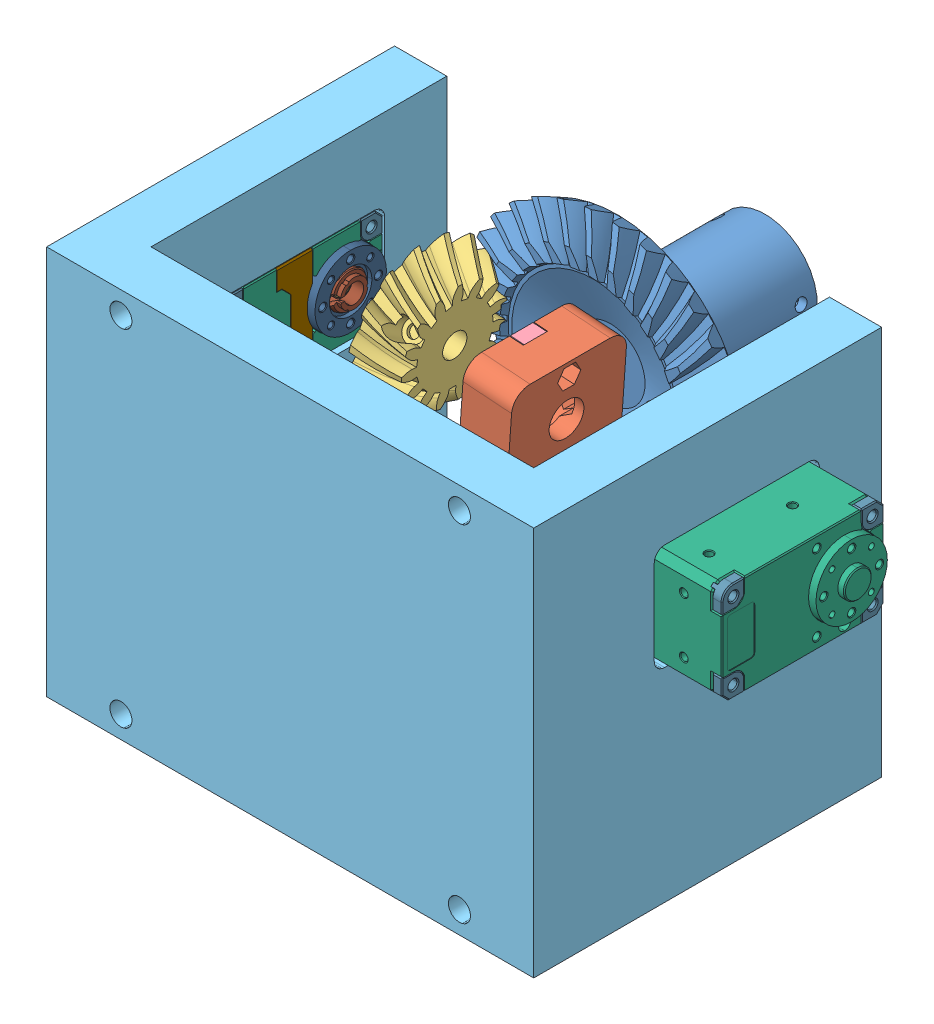
SolidWorks assembly ARMUS-100-000, configuration Défaut. Lengths in mm.
Overall size (185.8 148.44 136.49).
56 component instances, 14 part files, 17 mates.
Components (placement in the parent):
- ARMUS-100-001-1: ARMUS-100-001 [Default] at (-113.5896 14.9753 27.4558) x (-0.928119 0.372284 0) z (0 0 1) size (98.61 98.7 51.05)
- ARMUS-100-002-1: ARMUS-100-002 [Default] at (-113.5896 14.9753 49.0303) x (0.070839 0.997488 0) z (0.997488 -0.070839 0) size (29.97 33 14)
- ARMUS-100-003-1: ARMUS-100-003 [Default] at (-151.1032 17.6395 49.0303) x (0.0431 0.606897 -0.793611) z (0.997488 -0.070839 0) size (43.82 43.82 12.4)
- ARMUS-100-003-2: ARMUS-100-003 [Default] at (-74.4243 12.1939 49.0303) x (-0.070618 -0.99438 -0.078881) z (-0.997488 0.070839 0) size (43.82 43.82 12.4)
- ARMUS-100-004-1: ARMUS-100-004 [Default] at (-116.5821 15.1878 49.0303) x (0.070839 0.997488 0) z (-0.997488 0.070839 0) size (30 15.8 4)
- ARMUS-100-006-1: ARMUS-100-006 [Défaut] at (-74.0766 50.6459 21.4485) size (177.55 139.4 100)
- ARMUS-100-005.stp-1: ARMUS-100-005.stp [Défaut] at (-185.6063 17.2977 51.066) x (0 1 0) z (-1 0 0) size (28.5 46.5 40.9)
  - DC11_A01_DUMMY.stp-1: DC11_A01_DUMMY.stp [Défaut] at origin size (28.5 46.5 37.9)
  - DX124_SCREW-COVER.stp-1: DX124_SCREW-COVER.stp [Défaut] at (11.75 0 13.7) x (-1 0 0) z (0 1 0) size (3.5 30.65 3.5)
  - B3B-EH.stp-1: B3B-EH.stp [Défaut] at (10.15 -14.1 -3.8) x (0 -1 0) z (1 0 0) size (10 9.2 3.8)
  - B3B-EH.stp-2: B3B-EH.stp [Défaut] at (-10.15 -14.1 -3.8) x (0 1 0) z (-1 0 0) size (10 9.2 3.8)
  - DC11_A01_CASE_CVR_DUMMY.stp-1: DC11_A01_CASE_CVR_DUMMY.stp [Défaut] at origin size (28.3 17.62 8.31)
  - DC11_A01_IDLER_DUMMY.stp-1: DC11_A01_IDLER_DUMMY.stp [Défaut] at (0 0 -19) x (1 0 0) z (0 1 0) size (20.5 3.5 20.5)
  - DC11_A01_IDLER_CAP_DUMMY.stp-1: DC11_A01_IDLER_CAP_DUMMY.stp [Défaut] at (0 0 -18.8) x (1 0 0) z (0 -1 0) size (10.1 5.2 10.37)
  - DC11_A01_IDLER_SCREW.stp-1: DC11_A01_IDLER_SCREW.stp [Défaut] at (0 0 -15.1) x (-1 0 0) z (0 -1 0) size (5 5.01 5)
  - FHS_M2_5X10.stp-1: FHS_M2_5X10.stp [Défaut] at (11 8 12.95) x (-1 0 0) z (0 1 0) size (5 10.01 5)
  - FHS_M2_5X10.stp-2: FHS_M2_5X10.stp [Défaut] at (-11 8 12.95) x (-1 0 0) z (0 1 0) size (5 10.01 5)
  - FHS_M2_5X10.stp-3: FHS_M2_5X10.stp [Défaut] at (-11 -32 12.95) x (-1 0 0) z (0 1 0) size (5 10.01 5)
  - FHS_M2_5X10.stp-4: FHS_M2_5X10.stp [Défaut] at (11 -32 12.95) x (-1 0 0) z (0 1 0) size (5 10.01 5)
  - FHS_M2_5X10.stp-5: FHS_M2_5X10.stp [Défaut] at (-11 8 -12.95) x (1 0 0) z (0 1 0) size (5 10.01 5)
  - FHS_M2_5X10.stp-6: FHS_M2_5X10.stp [Défaut] at (11 8 -12.95) x (1 0 0) z (0 1 0) size (5 10.01 5)
  - FHS_M2_5X10.stp-7: FHS_M2_5X10.stp [Défaut] at (-11 -32 -12.95) x (1 0 0) z (0 1 0) size (5 10.01 5)
  - FHS_M2_5X10.stp-8: FHS_M2_5X10.stp [Défaut] at (11 -32 -12.95) x (1 0 0) z (0 1 0) size (5 10.01 5)
  - DC11_A01_SPACER_DUMMY.stp-1: DC11_A01_SPACER_DUMMY.stp [Défaut] at (11 8 14.2) x (-1 0 0) z (0 0 1) size (6.5 6.5 3.9)
  - DC11_A01_SPACER_DUMMY.stp-2: DC11_A01_SPACER_DUMMY.stp [Défaut] at (-11 8 14.2) x (0 -1 0) z (0 0 1) size (6.5 6.5 3.9)
  - DC11_A01_SPACER_DUMMY.stp-3: DC11_A01_SPACER_DUMMY.stp [Défaut] at (-11 -32 14.2) x (-1 0 0) z (0 0 1) size (6.5 6.5 3.9)
  - DC11_A01_SPACER_DUMMY.stp-4: DC11_A01_SPACER_DUMMY.stp [Défaut] at (11 -32 14.2) x (0 1 0) z (0 0 1) size (6.5 6.5 3.9)
  - DC11_A01_SPACER_DUMMY.stp-5: DC11_A01_SPACER_DUMMY.stp [Défaut] at (11 8 -14.2) x (0 -1 0) z (0 0 -1) size (6.5 6.5 3.9)
  - DC11_A01_SPACER_DUMMY.stp-6: DC11_A01_SPACER_DUMMY.stp [Défaut] at (-11 8 -14.2) x (1 0 0) z (0 0 -1) size (6.5 6.5 3.9)
  - DC11_A01_SPACER_DUMMY.stp-7: DC11_A01_SPACER_DUMMY.stp [Défaut] at (11 -32 -14.2) x (-1 0 0) z (0 0 -1) size (6.5 6.5 3.9)
  - DC11_A01_SPACER_DUMMY.stp-8: DC11_A01_SPACER_DUMMY.stp [Défaut] at (-11 -32 -14.2) x (0 1 0) z (0 0 -1) size (6.5 6.5 3.9)
- ARMUS-100-005.stp-2: ARMUS-100-005.stp [Défaut] at (-41.6063 17.2977 51.066) x (0 -1 0) z (1 0 0) size (28.5 46.5 40.9)
  - DC11_A01_DUMMY.stp-1: DC11_A01_DUMMY.stp [Défaut] at origin size (28.5 46.5 37.9)
  - DX124_SCREW-COVER.stp-1: DX124_SCREW-COVER.stp [Défaut] at (11.75 0 13.7) x (-1 0 0) z (0 1 0) size (3.5 30.65 3.5)
  - B3B-EH.stp-1: B3B-EH.stp [Défaut] at (10.15 -14.1 -3.8) x (0 -1 0) z (1 0 0) size (10 9.2 3.8)
  - B3B-EH.stp-2: B3B-EH.stp [Défaut] at (-10.15 -14.1 -3.8) x (0 1 0) z (-1 0 0) size (10 9.2 3.8)
  - DC11_A01_CASE_CVR_DUMMY.stp-1: DC11_A01_CASE_CVR_DUMMY.stp [Défaut] at origin size (28.3 17.62 8.31)
  - DC11_A01_IDLER_DUMMY.stp-1: DC11_A01_IDLER_DUMMY.stp [Défaut] at (0 0 -19) x (1 0 0) z (0 1 0) size (20.5 3.5 20.5)
  - DC11_A01_IDLER_CAP_DUMMY.stp-1: DC11_A01_IDLER_CAP_DUMMY.stp [Défaut] at (0 0 -18.8) x (1 0 0) z (0 -1 0) size (10.1 5.2 10.37)
  - DC11_A01_IDLER_SCREW.stp-1: DC11_A01_IDLER_SCREW.stp [Défaut] at (0 0 -15.1) x (-1 0 0) z (0 -1 0) size (5 5.01 5)
  - FHS_M2_5X10.stp-1: FHS_M2_5X10.stp [Défaut] at (11 8 12.95) x (-1 0 0) z (0 1 0) size (5 10.01 5)
  - FHS_M2_5X10.stp-2: FHS_M2_5X10.stp [Défaut] at (-11 8 12.95) x (-1 0 0) z (0 1 0) size (5 10.01 5)
  - FHS_M2_5X10.stp-3: FHS_M2_5X10.stp [Défaut] at (-11 -32 12.95) x (-1 0 0) z (0 1 0) size (5 10.01 5)
  - FHS_M2_5X10.stp-4: FHS_M2_5X10.stp [Défaut] at (11 -32 12.95) x (-1 0 0) z (0 1 0) size (5 10.01 5)
  - FHS_M2_5X10.stp-5: FHS_M2_5X10.stp [Défaut] at (-11 8 -12.95) x (1 0 0) z (0 1 0) size (5 10.01 5)
  - FHS_M2_5X10.stp-6: FHS_M2_5X10.stp [Défaut] at (11 8 -12.95) x (1 0 0) z (0 1 0) size (5 10.01 5)
  - FHS_M2_5X10.stp-7: FHS_M2_5X10.stp [Défaut] at (-11 -32 -12.95) x (1 0 0) z (0 1 0) size (5 10.01 5)
  - FHS_M2_5X10.stp-8: FHS_M2_5X10.stp [Défaut] at (11 -32 -12.95) x (1 0 0) z (0 1 0) size (5 10.01 5)
  - DC11_A01_SPACER_DUMMY.stp-1: DC11_A01_SPACER_DUMMY.stp [Défaut] at (11 8 14.2) x (-1 0 0) z (0 0 1) size (6.5 6.5 3.9)
  - DC11_A01_SPACER_DUMMY.stp-2: DC11_A01_SPACER_DUMMY.stp [Défaut] at (-11 8 14.2) x (0 -1 0) z (0 0 1) size (6.5 6.5 3.9)
  - DC11_A01_SPACER_DUMMY.stp-3: DC11_A01_SPACER_DUMMY.stp [Défaut] at (-11 -32 14.2) x (-1 0 0) z (0 0 1) size (6.5 6.5 3.9)
  - DC11_A01_SPACER_DUMMY.stp-4: DC11_A01_SPACER_DUMMY.stp [Défaut] at (11 -32 14.2) x (0 1 0) z (0 0 1) size (6.5 6.5 3.9)
  - DC11_A01_SPACER_DUMMY.stp-5: DC11_A01_SPACER_DUMMY.stp [Défaut] at (11 8 -14.2) x (0 -1 0) z (0 0 -1) size (6.5 6.5 3.9)
  - DC11_A01_SPACER_DUMMY.stp-6: DC11_A01_SPACER_DUMMY.stp [Défaut] at (-11 8 -14.2) x (1 0 0) z (0 0 -1) size (6.5 6.5 3.9)
  - DC11_A01_SPACER_DUMMY.stp-7: DC11_A01_SPACER_DUMMY.stp [Défaut] at (11 -32 -14.2) x (-1 0 0) z (0 0 -1) size (6.5 6.5 3.9)
  - DC11_A01_SPACER_DUMMY.stp-8: DC11_A01_SPACER_DUMMY.stp [Défaut] at (-11 -32 -14.2) x (0 1 0) z (0 0 -1) size (6.5 6.5 3.9)
Mates (geometry in assembly coordinates):
- Coïncidente12: coincident anti-aligned: line of ARMUS-100-002-1 through (-115.5195 30.1502 52.5303) axis (0 0 -1); line of ARMUS-100-004-1 through (-115.5195 30.1502 45.7803) axis (0 0 1)
- Coaxiale9: concentric aligned: cylinder of ARMUS-100-001-1 through (-113.5896 14.9753 27.4558) axis (0 0 -1) radius 8.2; cylinder of ARMUS-100-002-1 through (-113.5896 14.9753 32.5303) axis (0 0 -1) radius 2.6
- Coaxiale10: concentric anti-aligned: cylinder of ARMUS-100-002-1 through (-120.572 15.4712 49.0303) axis (-0.997488 0.070839 0) radius 5; cylinder of ARMUS-100-004-1 through (-116.5821 15.1878 49.0303) axis (0.997488 -0.070839 0) radius 5
- Coaxiale13: concentric: cylinder of ARMUS-100-003-1 through (-144.7193 17.1861 49.0303) axis (0.997488 -0.070839 0) radius 2.6; cylinder of ARMUS-100-004-1 through (-116.5821 15.1878 49.0303) axis (0.997488 -0.070839 0) radius 5
- Coaxiale14: concentric: cylinder of ARMUS-100-002-1 through (-120.572 15.4712 49.0303) axis (-0.997488 0.070839 0) radius 5; cylinder of ARMUS-100-003-2 through (-80.8082 12.6473 49.0303) axis (-0.997488 0.070839 0) radius 2.6
- Contr.Engrenages3: gear = 16.4 : 5.2 mm: cylinder of ARMUS-100-003-1 through (-144.7193 17.1861 49.0303) axis (0.997488 -0.070839 0) radius 2.6; cylinder of ARMUS-100-001-1 through (-113.5896 14.9753 27.4558) axis (0 0 -1) radius 8.2
- Contr.Engrenages4: gear = 16.4 : 5.2 mm: cylinder of ARMUS-100-003-2 through (-80.8082 12.6473 49.0303) axis (-0.997488 0.070839 0) radius 2.6; cylinder of ARMUS-100-001-1 through (-113.5896 14.9753 27.4558) axis (0 0 -1) radius 8.2
- Distance1: distance = 24.2081 mm: plane of ARMUS-100-004-1 through (-120.572 15.4712 49.0303) normal (-0.997488 0.070839 0); plane of ARMUS-100-003-1 through (-144.7193 17.1861 49.0303) normal (0.997488 -0.070839 0)
- Distance2: distance = 35.864 mm: plane of ARMUS-100-004-1 through (-116.5821 15.1878 49.0303) normal (0.997488 -0.070839 0); plane of ARMUS-100-003-2 through (-80.8082 12.6473 49.0303) normal (-0.997488 0.070839 0)
- Parallèle2: parallel aligned: plane of ARMUS-100-006-1 through (-183.6063 55.0598 121.4485) normal (0 1 0); plane of ARMUS-100-005.stp-1/DC11_A01_DUMMY.stp-1 through (-202.6063 31.5477 84.316) normal (0 1 0)
- Parallèle3: parallel aligned: plane of ARMUS-100-006-1 through (-74.0766 50.6459 21.4485) normal (0 0 -1); plane of ARMUS-100-005.stp-1/DC11_A01_DUMMY.stp-1 through (-202.6063 29.5477 39.816) normal (0 0 -1)
- Parallèle4: parallel: line of ARMUS-100-006-1 through (-183.6063 55.0598 121.4485) axis (0 -1 0); plane of ARMUS-100-005.stp-1/DC11_A01_DUMMY.stp-1 through (-202.6063 17.2977 51.066) normal (-1 0 0)
- Coïncidente22: coincident aligned: plane of ARMUS-100-006-1 through (-168.6063 -56.9402 21.4485) normal (1 0 0); plane of ARMUS-100-005.stp-1/DC11_A01_DUMMY.stp-1 through (-168.6063 17.2977 51.066) normal (1 0 0)
- Parallèle5: parallel aligned: plane of ARMUS-100-006-1 through (-183.6063 55.0598 121.4485) normal (0 1 0); plane of ARMUS-100-005.stp-2/DC11_A01_DUMMY.stp-1 through (-24.6063 31.5477 41.816) normal (0 1 0)
- Coaxiale15: concentric anti-aligned: cylinder of ARMUS-100-005.stp-1/DC11_A01_IDLER_CAP_DUMMY.stp-1 through (-166.8063 17.2977 51.066) axis (1 0 0) radius 2.75; cone of ARMUS-100-005.stp-2/DC11_A01_IDLER_CAP_DUMMY.stp-1 through (-60.0063 17.2977 51.066) axis (-1 0 0)
- Coïncidente24: coincident aligned: plane of ARMUS-100-006-1 through (-58.6063 -56.9402 21.4485) normal (-1 0 0); plane of ARMUS-100-005.stp-2/DC11_A01_DUMMY.stp-1 through (-58.6063 17.2977 51.066) normal (-1 0 0)
- Distance3: distance = 3.0745 mm anti-aligned: plane of ARMUS-100-001-1 through (-113.5896 14.9753 29.4558) normal (0 0 1); plane of ARMUS-100-002-1 through (-121.2804 5.4963 32.5303) normal (0 0 -1)
